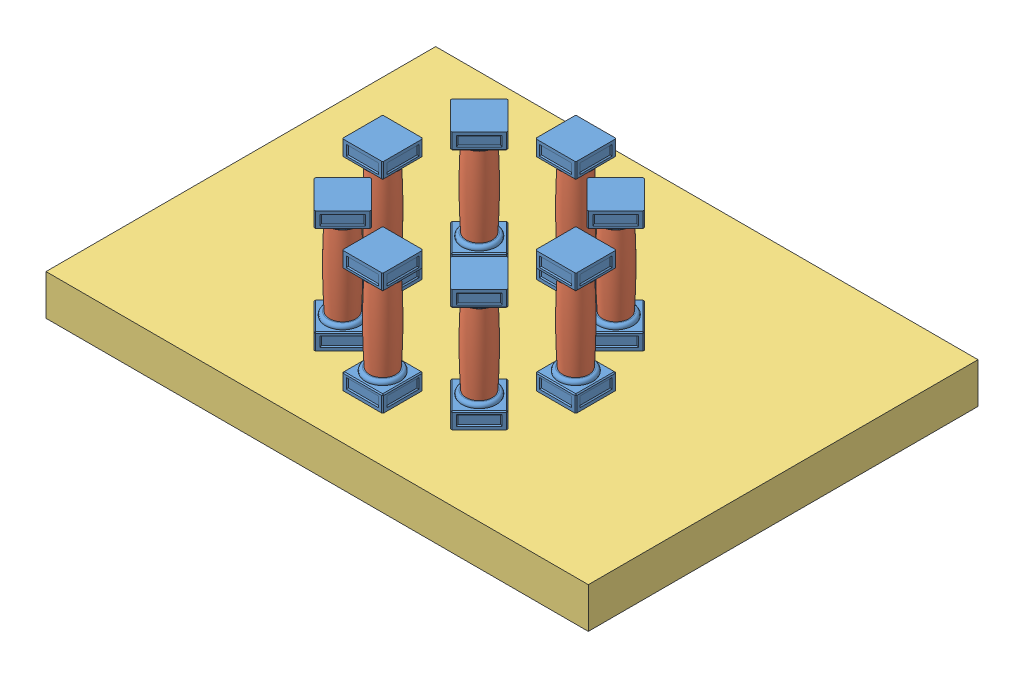
SolidWorks assembly portal, configuration Default. Lengths in mm.
Overall size (2678.05 830.86 1924.25).
25 component instances, 3 part files, 6 mates.
Components (placement in the parent):
- capital-1: capital [Default] at (0 0 43.7816) x (-1 0 0) z (0 1 0) size (200 200 150.86)
- column-1: column [Default] at (100 100 0) size (141.12 400 141.12)
- capital-2: capital [Default] at (200 600 43.7816) x (1 0 0) z (0 -1 0) size (200 200 150.86)
- floor^portal-1: floor^portal [Default] x (-1 0 0) z (0 1 0) size (2678.05 1924.25 200) (virtual)
- capital-3: capital [Default] at (341.2862 600 297.3136) x (0.707107 0 -0.707107) z (0 -1 0) size (200 200 150.86)
- capital-4: capital [Default] at (620.4649 600 376.6833) x (0 0 -1) z (0 -1 0) size (200 200 150.86)
- capital-5: capital [Default] at (873.9969 600 235.3971) x (-0.707107 0 -0.707107) z (0 -1 0) size (200 200 150.86)
- capital-6: capital [Default] at (953.3666 600 -43.7816) x (-1 0 0) z (0 -1 0) size (200 200 150.86)
- capital-7: capital [Default] at (812.0804 600 -297.3136) x (-0.707107 0 0.707107) z (0 -1 0) size (200 200 150.86)
- capital-8: capital [Default] at (532.9017 600 -376.6833) x (0 0 1) z (0 -1 0) size (200 200 150.86)
- capital-9: capital [Default] at (279.3697 600 -235.3971) x (0.707107 0 0.707107) z (0 -1 0) size (200 200 150.86)
- column-2: column [Default] at (239.6173 100 337.066) x (0.707107 0 -0.707107) z (0.707107 0 0.707107) size (141.12 400 141.12)
- column-3: column [Default] at (576.6833 100 476.6833) x (0 0 -1) z (1 0 0) size (141.12 400 141.12)
- column-4: column [Default] at (913.7493 100 337.066) x (-0.707107 0 -0.707107) z (0.707107 0 -0.707107) size (141.12 400 141.12)
- column-5: column [Default] at (1053.3666 100 0) x (-1 0 0) z (0 0 -1) size (141.12 400 141.12)
- column-6: column [Default] at (913.7493 100 -337.066) x (-0.707107 0 0.707107) z (-0.707107 0 -0.707107) size (141.12 400 141.12)
- column-7: column [Default] at (576.6833 100 -476.6833) x (0 0 1) z (-1 0 0) size (141.12 400 141.12)
- column-8: column [Default] at (239.6173 100 -337.066) x (0.707107 0 0.707107) z (-0.707107 0 0.707107) size (141.12 400 141.12)
- capital-10: capital [Default] at (199.8649 0 438.7349) x (-0.707107 0 0.707107) z (0 1 0) size (200 200 150.86)
- capital-11: capital [Default] at (620.4649 0 576.6833) x (0 0 1) z (0 1 0) size (200 200 150.86)
- capital-12: capital [Default] at (1015.4182 0 376.8184) x (0.707107 0 0.707107) z (0 1 0) size (200 200 150.86)
- capital-13: capital [Default] at (1153.3666 0 -43.7816) x (1 0 0) z (0 1 0) size (200 200 150.86)
- capital-14: capital [Default] at (953.5017 0 -438.7349) x (0.707107 0 -0.707107) z (0 1 0) size (200 200 150.86)
- capital-15: capital [Default] at (532.9017 0 -576.6833) x (0 0 -1) z (0 1 0) size (200 200 150.86)
- capital-16: capital [Default] at (137.9484 0 -376.8184) x (-0.707107 0 -0.707107) z (0 1 0) size (200 200 150.86)
Mates (geometry in assembly coordinates):
- Coincidente1: coincident anti-aligned: plane of capital-1 through (100 100 0) normal (0 1 0); plane of column-1 through (100 100 0) normal (0 -1 0)
- Concentrico1: concentric aligned: circle of capital-1; circle of column-1
- Coincidente2: coincident anti-aligned: plane of column-1 through (35 500 0) normal (0 1 0); plane of capital-2 through (100 500 0) normal (0 -1 0)
- Concentrico2: concentric anti-aligned: circle of column-1; circle of capital-2
- Parallelo1: parallel aligned: plane of capital-1 through (0 80 100) normal (-1 0 0); plane of capital-2 through (0 520 100) normal (-1 0 0)
- Coincidente3: coincident: moEndPointRef_w of capital-1; plane of assembly
